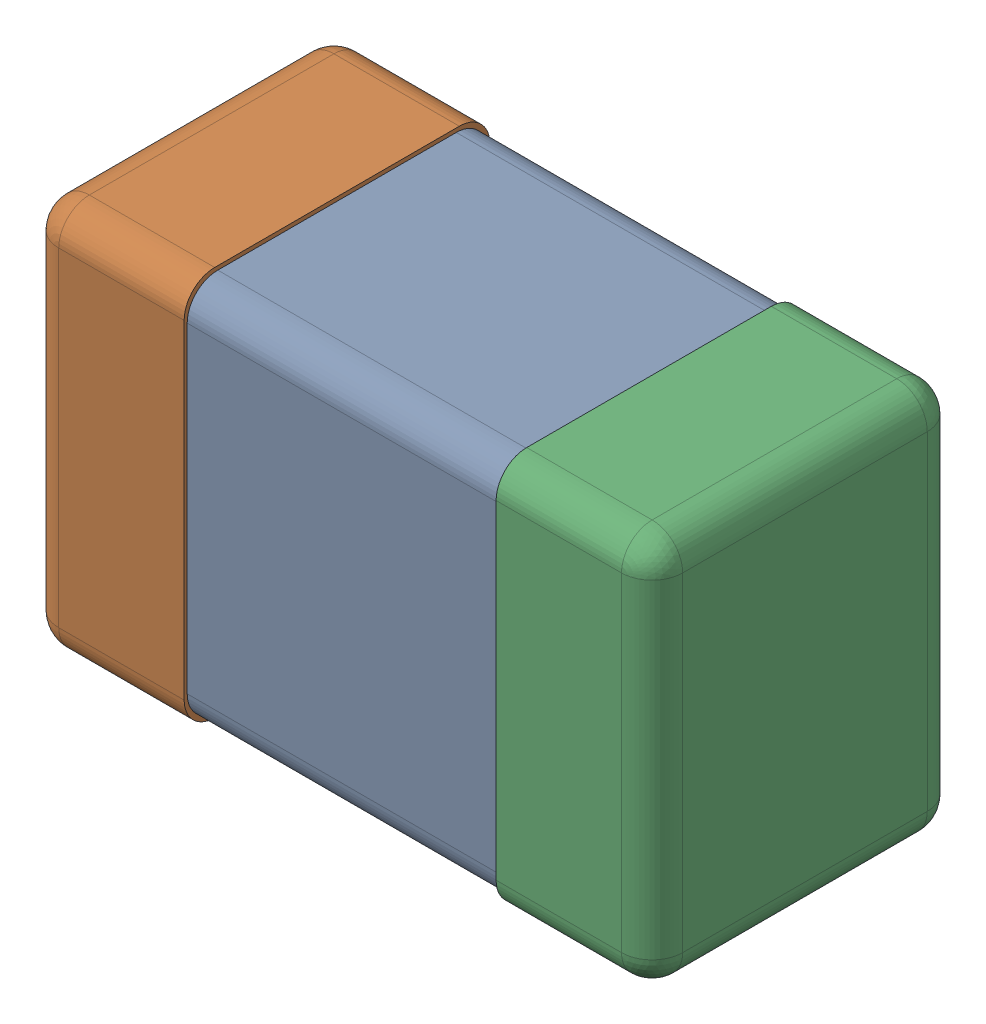
SolidWorks assembly C3, configuration Predeterminado. Lengths in mm.
Overall size (2 1.25 0.98).
4 component instances, 3 part files, 0 mates.
Components (placement in the parent):
- 6074688640-1: 6074688640 [Predeterminado] at (28 48.5 0) x (-1 0 0) z (0 0 1) size (2 1.25 0.98)
  - body2-1: body2 [Predeterminado] at origin size (1 1.22 0.96)
  - Fillet2-1: Fillet2 [Predeterminado] at origin size (0.5 1.25 0.98)
  - Fillet1-1: Fillet1 [Predeterminado] at origin size (0.5 1.25 0.98)
